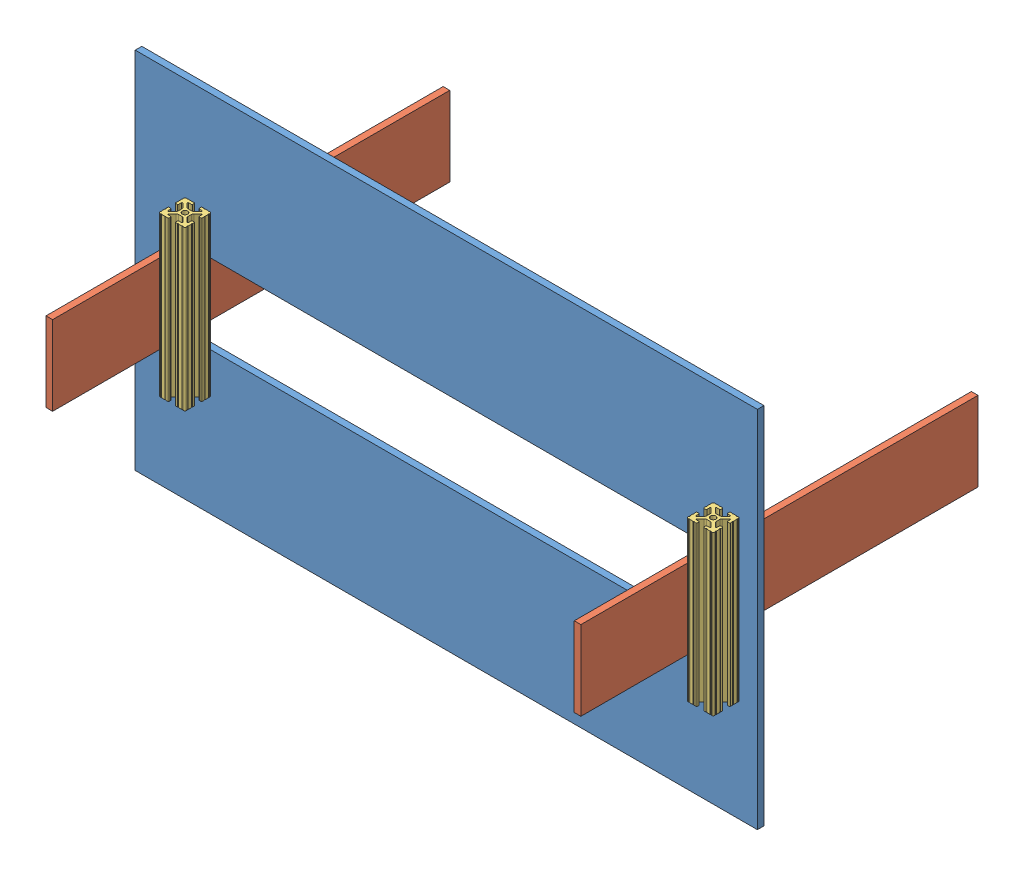
SolidWorks assembly Assem2, configuration Default. Lengths in mm.
Overall size (596.9 349.25 381).
9 component instances, 3 part files, 8 mates.
Components (placement in the parent):
- Irby-'Grabber' Faceplate-1: Irby-'Grabber' Faceplate [Default] at (214.8269 342.4564 438.173) size (596.9 349.25 6.35)
- Irby-'Grabber' Fork Final-1: Irby-'Grabber' Fork Final [Default] at (372.4372 -16.1553 -155.9819) size (57.15 152.4 381)
  - Irby-'Grabber' Fork P1-1: Irby-'Grabber' Fork P1 [Default] at (-414.6254 358.6118 537.0049) size (6.35 76.2 381)
  - modifiable_t-slot_bar__6_in_-1: modifiable_t-slot_bar__6_in_ [Default] at (-437.0351 284.753 566.2599) x (0 -1 0) z (0 0 1) size (152.4 25.4 25.4)
  - modifiable_t-slot_bar__6_in_-2: modifiable_t-slot_bar__6_in_ [Default] at (-468.7851 284.753 534.5099) x (0 -1 0) z (0 0 1) size (152.4 25.4 25.4)
- Irby-'Grabber' Fork Final-2: Irby-'Grabber' Fork Final [Default] at (879.199 -16.1553 -155.9819) size (57.15 152.4 381)
  - Irby-'Grabber' Fork P1-1: Irby-'Grabber' Fork P1 [Default] at (-414.6254 358.6118 537.0049) size (6.35 76.2 381)
  - modifiable_t-slot_bar__6_in_-1: modifiable_t-slot_bar__6_in_ [Default] at (-437.0351 284.753 566.2599) x (0 -1 0) z (0 0 1) size (152.4 25.4 25.4)
  - modifiable_t-slot_bar__6_in_-2: modifiable_t-slot_bar__6_in_ [Default] at (-468.7851 284.753 534.5099) x (0 -1 0) z (0 0 1) size (152.4 25.4 25.4)
Mates (geometry in assembly coordinates):
- Coincident1: coincident anti-aligned: plane of Irby-'Grabber' Faceplate-1 through (472.0019 380.5564 438.173) normal (0 -1 0); plane of Irby-'Grabber' Fork Final-1/Irby-'Grabber' Fork P1-1 through (-35.8383 380.5564 190.523) normal (0 1 0)
- Coincident2: coincident anti-aligned: plane of Irby-'Grabber' Faceplate-1 through (472.0019 304.3564 438.173) normal (0 1 0); plane of Irby-'Grabber' Fork Final-1/Irby-'Grabber' Fork P1-1 through (-35.8383 304.3564 190.523) normal (0 -1 0)
- Coincident3: coincident anti-aligned: plane of Irby-'Grabber' Faceplate-1 through (214.8269 342.4564 438.173) normal (0 0 -1); plane of Irby-'Grabber' Fork Final-1/modifiable_t-slot_bar__6_in_-2 through (-67.5883 266.2564 438.173) normal (0 0 1)
- Coincident4: coincident anti-aligned: plane of Irby-'Grabber' Faceplate-1 through (214.8269 342.4564 444.523) normal (0 0 1); plane of Irby-'Grabber' Fork Final-1/modifiable_t-slot_bar__6_in_-1 through (-35.8383 266.2564 444.523) normal (0 0 -1)
- Coincident5: coincident anti-aligned: plane of Irby-'Grabber' Faceplate-1 through (214.8269 342.4564 438.173) normal (0 0 -1); plane of Irby-'Grabber' Fork Final-2/modifiable_t-slot_bar__6_in_-2 through (439.1736 266.2564 438.173) normal (0 0 1)
- Coincident7: coincident anti-aligned: plane of Irby-'Grabber' Faceplate-1 through (214.8269 342.4564 444.523) normal (0 0 1); plane of Irby-'Grabber' Fork Final-2/modifiable_t-slot_bar__6_in_-1 through (470.9236 266.2564 444.523) normal (0 0 -1)
- Coincident8: coincident anti-aligned: plane of Irby-'Grabber' Faceplate-1 through (472.0019 380.5564 438.173) normal (0 -1 0); plane of Irby-'Grabber' Fork Final-2/Irby-'Grabber' Fork P1-1 through (470.9236 380.5564 190.523) normal (0 1 0)
- Coincident9: coincident anti-aligned: plane of Irby-'Grabber' Faceplate-1 through (472.0019 304.3564 438.173) normal (0 1 0); plane of Irby-'Grabber' Fork Final-2/Irby-'Grabber' Fork P1-1 through (470.9236 304.3564 190.523) normal (0 -1 0)
